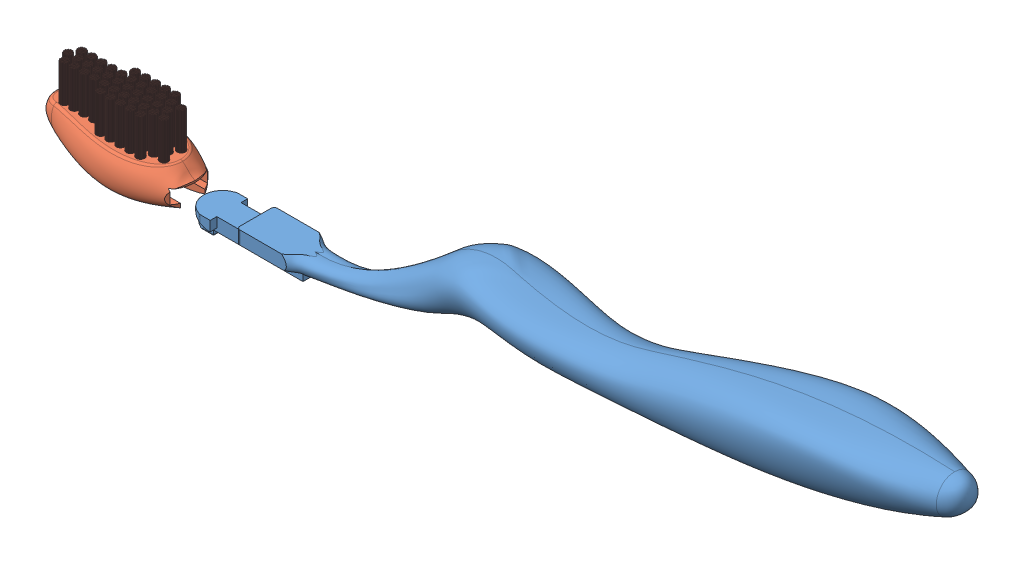
SolidWorks assembly Toothbrush Assem, configuration Default. Lengths in mm.
Overall size (276.97 47.02 24.24).
2 component instances, 2 part files, 2 mates.
Components (placement in the parent):
- Toothbrush - Handle-1: Toothbrush - Handle [Default] at (-30.1068 -7.9996 35.0111) size (238.22 47.02 24.24)
- Toothbrush - Head-1: Toothbrush - Head [Default] at (-64.3693 -7.9896 35.0111) size (237.48 39.62 22.2)
Mates (geometry in assembly coordinates):
- Coincident4: coincident anti-aligned: plane of toothbrush  - handle-1 through (-72.6068 0.0004 22.8889) normal (0 1 0); plane of toothbrush - Copy-1 through (-54.3694 0.0004 35.0111) normal (0 -1 0)
- Coincident5: coincident anti-aligned: plane of toothbrush  - handle-1 through (-19.1068 -4.9996 40.6661) normal (0 0 1); plane of toothbrush - Copy-1 through (-53.3694 -3.9996 40.6661) normal (0 0 -1)
